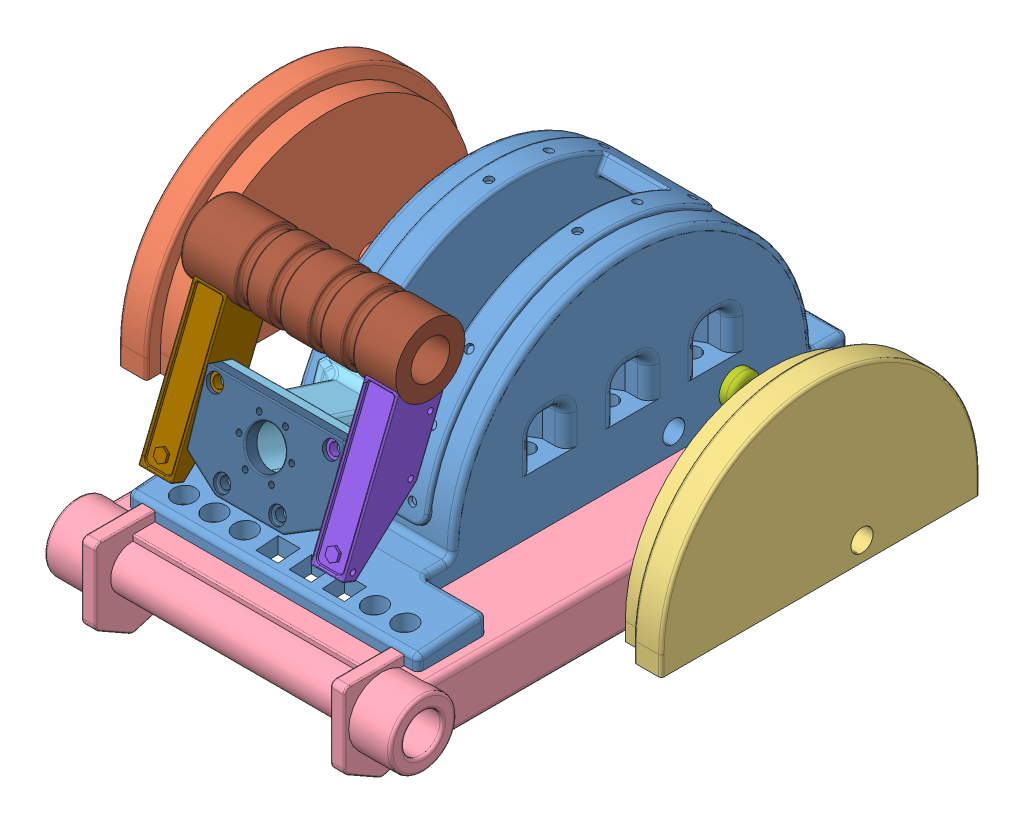
SolidWorks assembly HOTAS, configuration Default. Lengths in mm.
Overall size (196 123.34 201.5).
11 component instances, 11 part files, 15 mates.
Components (placement in the parent):
- HOTAS-1: HOTAS [Default] at (-24.5385 48.7881 217.2401) size (105 73.44 178)
- Lunetta SX-1: Lunetta SX [Default] at (-44.5385 0 0) x (0 0 1) z (-1 0 0) size (115 64.5 18)
- MirrorLunetta SX-2: MirrorLunetta SX [Default] at (115.4615 0 0) x (0 0 1) z (-1 0 0) size (115 64.5 18)
- Base^HOTAS-1: Base^HOTAS [Default] at (0 48.7881 0) x (-1 0 0) z (0 -1 0) size (125 201.5 34.41) (virtual)
- Asse Manetta^HOTAS-1: Asse Manetta^HOTAS [Default] at (46.4615 4.5065 -2.7229) x (0 -0.050829 0.998707) z (-1 0 0) size (131.62 68.55 50) (virtual)
- Ingranaggio manetta^HOTAS-1: Ingranaggio manetta^HOTAS [Default] at (23.9615 0 0) x (0 0 -1) z (1 0 0) size (32.17 42.29 10) (virtual)
- Perno ingranaggio manetta^HOTAS-1: Perno ingranaggio manetta^HOTAS [Default] at (27.4615 0 0) x (0 0 -1) z (1 0 0) size (12 12 46.5) (virtual)
- Supporto manetta^HOTAS-1: Supporto manetta^HOTAS [Default] at (59.9615 -3.0983 -9.5079) x (0 0 -1) z (1 0 0) size (36.63 51.31 22.05) (virtual)
- MirrorSupporto manetta^HOTAS-2: MirrorSupporto manetta^HOTAS [Default] at (9.9615 -3.0983 -9.5079) x (0 0 -1) z (1 0 0) size (36.63 51.31 22.05) (virtual)
- Blocco supporto manetta^HOTAS-1: Blocco supporto manetta^HOTAS [Default] at (0 67.8188 208.1212) x (1 0 0) z (0 0.309827 0.950793) size (50 32 4.5) (virtual)
- Manetta^HOTAS-1: Manetta^HOTAS [Default] at (71.9615 -3.0983 -9.5079) x (0 0 -1) z (1 0 0) size (25 25 78) (virtual)
Mates (geometry in assembly coordinates):
- Distance1: distance = 0 mm anti-aligned: plane of Base^HOTAS-1 through (-22.0385 48.7881 202.2401) normal (0 1 0); plane of HOTAS-1 through (-24.5385 48.7881 217.2401) normal (0 -1 0)
- Distance2: distance = 50 mm anti-aligned: plane of Lunetta SX-1 through (-44.5385 55.7881 102.2401) normal (1 0 0); plane of HOTAS-1 through (5.4615 55.7881 177.2401) normal (-1 0 0)
- Concentric1: concentric anti-aligned: circle of HOTAS-1; circle of Asse Manetta^HOTAS-1
- Hinge1: hinge = 2.96706 rad anti-aligned: circle of Asse Manetta^HOTAS-1; circle of HOTAS-1; plane of Asse Manetta^HOTAS-1 through (23.9615 55.7881 87.2401) normal (-1 0 0); plane of HOTAS-1 through (23.9615 45.7881 162.2401) normal (1 0 0); plane of Asse Manetta^HOTAS-1 through (23.9615 48.0126 98.8824) normal (0 -0.950793 0.309827); plane of HOTAS-1 through (-125.4224 66.5365 161.2696) normal (0 0.990149 -0.140017)
- Coincident1: coincident anti-aligned: plane of Asse Manetta^HOTAS-1; plane of Blocco supporto manetta^HOTAS-1
- Coincident3: coincident aligned: plane of Asse Manetta^HOTAS-1; plane of Blocco supporto manetta^HOTAS-1
- Concentric2: concentric anti-aligned: cylinder of Asse Manetta^HOTAS-1 through (34.9615 48.247 64.0981) axis (0 0.309827 0.950793) radius 7; cylinder of Blocco supporto manetta^HOTAS-1 through (34.9615 111.8742 259.356) axis (0 -0.309827 -0.950793) radius 7
- Parallel3: parallel aligned: plane of Supporto manetta^HOTAS-1; plane of MirrorSupporto manetta^HOTAS-2
- Parallel4: parallel aligned: plane of Supporto manetta^HOTAS-1; plane of MirrorSupporto manetta^HOTAS-2
- Tangent1: tangent: circle of MirrorSupporto manetta^HOTAS-2; cylinder of Manetta^HOTAS-1 through (-6.0385 128.7107 181.7132) axis (1 0 0) radius 12.5
- Coincident9: coincident aligned: plane of Supporto manetta^HOTAS-1 through (71.9615 128.7107 181.7132) normal (1 0 0); plane of Manetta^HOTAS-1 through (71.9615 128.7107 181.7132) normal (1 0 0)
- Parallel7: parallel aligned: plane of MirrorSupporto manetta^HOTAS-2; plane of Blocco supporto manetta^HOTAS-1
- Concentric4: concentric aligned: cylinder of Asse Manetta^HOTAS-1 through (13.9615 99.5603 192.5191) axis (0 0.309827 0.950793) radius 2; cylinder of MirrorSupporto manetta^HOTAS-2 through (13.9615 101.1095 197.273) axis (0 0.309827 0.950793) radius 2
- Concentric5: concentric aligned: cylinder of Asse Manetta^HOTAS-1 through (55.9615 99.5603 192.5191) axis (0 0.309827 0.950793) radius 2; cylinder of Supporto manetta^HOTAS-1 through (55.9615 101.1095 197.273) axis (0 0.309827 0.950793) radius 2
- Coincident13: coincident aligned: plane of MirrorSupporto manetta^HOTAS-2; circle of Blocco supporto manetta^HOTAS-1
